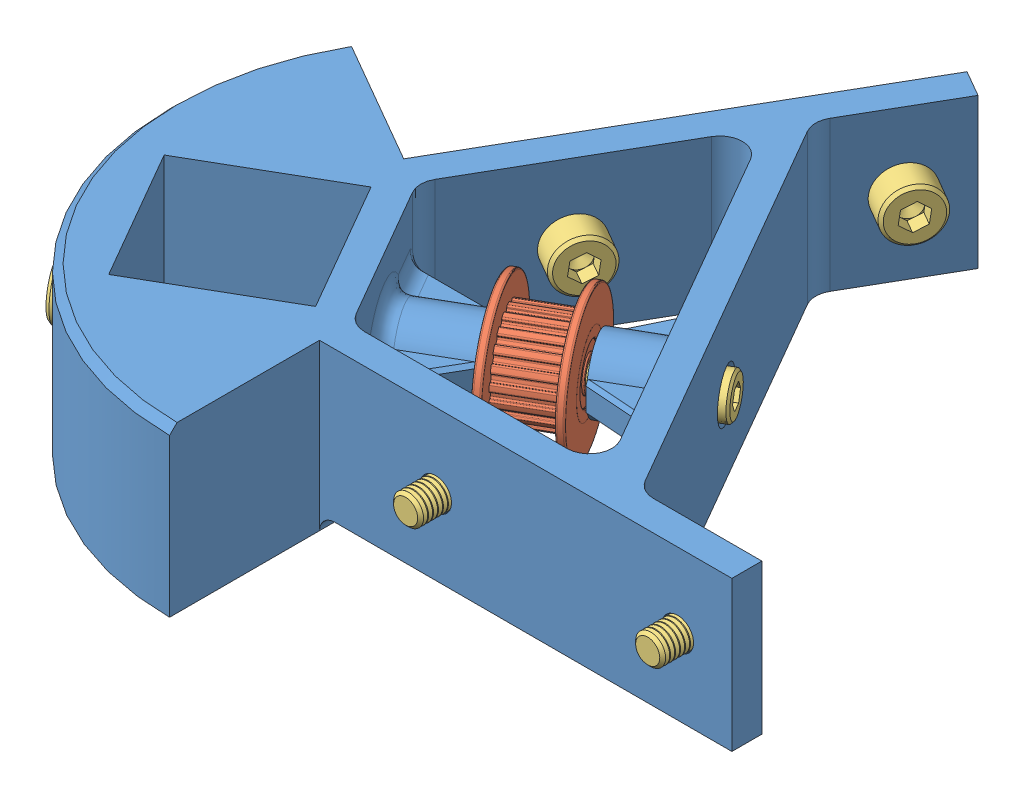
SolidWorks assembly Timing Assembly, configuration Default. Lengths in mm.
Overall size (92.71 23 94.2).
8 component instances, 3 part files, 14 mates.
Components (placement in the parent):
- Top Corner Support-1: Top Corner Support [Default] at origin size (92.71 23 94.2)
- Timing Pulley-1: Timing Pulley [Default] at (58.7441 9.7289 -33.9159) x (0.494167 0.152298 0.855923) z (-0.866025 0 0.5) size (17.85 17.85 9.2)
- socket head cap screw_am-1: socket head cap screw_am [B18.3.1M - 3 x 0.5 x 35 Hex SHCS -- 18SHX] at (72.0353 9.7289 -41.5896) x (-0.866025 0 0.5) z (-0.435421 -0.491563 -0.754171) size (38 5.5 5.5)
- socket head cap screw_am-2: socket head cap screw_am [B18.3.1M - 4 x 0.7 x 8 Hex SHCS -- 8SHX] at (95.7707 10 -18) x (0 0 1) z (-0.923728 -0.383049 0) size (12 7 7)
- socket head cap screw_am-3: socket head cap screw_am [B18.3.1M - 4 x 0.7 x 8 Hex SHCS -- 8SHX] at (63.4876 10 -18) x (0 0 1) z (-0.923728 -0.383049 0) size (12 7 7)
- socket head cap screw_am-4: socket head cap screw_am [B18.3.1M - 4 x 0.7 x 8 Hex SHCS -- 8SHX] at (47.3323 10 -45.9819) x (-0.866025 0 -0.5) z (-0.190925 0.924225 0.330691) size (12 7 7)
- socket head cap screw_am-5: socket head cap screw_am [B18.3.1M - 4 x 0.7 x 8 Hex SHCS -- 8SHX] at (63.4738 10 -73.9399) x (-0.866025 0 -0.5) z (-0.190925 0.924225 0.330691) size (12 7 7)
- socket head cap screw_am-6: socket head cap screw_am [B18.3.1M - 4 x 0.7 x 8 Hex SHCS -- 8SHX] at (14.3627 10 -8.2923) x (0.866025 0 -0.5) z (0.5 0 0.866025) size (12 7 7)
Mates (geometry in assembly coordinates):
- Concentric1: concentric: cylinder of Top Corner Support-1 through (35.7227 9.7289 -20.6245) axis (0.866025 0 -0.5) radius 1.25; cylinder of Timing Pulley-1 through (65.7339 9.7289 -37.9515) axis (-0.866025 0 0.5) radius 1.5
- Distance1: distance = 0.8473 mm: plane of Top Corner Support-1 through (50.909 10 -29.3923) normal (0.866025 0 -0.5); plane of Timing Pulley-1 through (51.6427 9.7289 -29.8159) normal (-0.866025 0 0.5)
- Concentric2: concentric: cylinder of Top Corner Support-1 through (69.4372 9.7289 -40.0896) axis (0.866025 0 -0.5) radius 2.75; cylinder of socket head cap screw_am-1 through (99.5316 9.7289 -57.4646) axis (0.866025 0 -0.5) radius 2.75
- Coincident2: coincident: plane of Top Corner Support-1 through (69.4372 9.7289 -40.0896) normal (0.866025 0 -0.5); plane of socket head cap screw_am-1 through (68.7613 12.1238 -41.2603) normal (-0.866025 0 0.5)
- Concentric3: concentric: cylinder of Top Corner Support-1 through (35.1989 10 -52.9871) axis (0.866025 0 0.5) radius 2.125; cylinder of socket head cap screw_am-4 through (74.8286 10 -30.1069) axis (0.866025 0 0.5) radius 3.5
- Concentric4: concentric: cylinder of Top Corner Support-1 through (51.3405 10 -80.9451) axis (0.866025 0 0.5) radius 2.125; cylinder of socket head cap screw_am-5 through (90.9701 10 -58.0649) axis (0.866025 0 0.5) radius 3.5
- Concentric5: concentric: cylinder of Top Corner Support-1 through (63.4876 10 -3.9896) axis (0 0 -1) radius 2.125; cylinder of socket head cap screw_am-3 through (63.4876 10 -49.75) axis (0 0 -1) radius 3.5
- Concentric6: concentric: cylinder of Top Corner Support-1 through (95.7707 10 -3.9896) axis (0 0 -1) radius 2.125; cylinder of socket head cap screw_am-2 through (95.7707 10 -49.75) axis (0 0 -1) radius 3.5
- Concentric7: concentric: cylinder of Top Corner Support-1 through (26.4961 10 -15.2975) axis (-0.866025 0 0.5) radius 2.125; cylinder of socket head cap screw_am-6 through (-13.1336 10 7.5827) axis (-0.866025 0 0.5) radius 3.5
- Coincident3: coincident: plane of Top Corner Support-1 through (17.8268 10 -10.2923) normal (-0.866025 0 0.5); plane of socket head cap screw_am-6 through (17.8268 13.5 -10.2923) normal (0.866025 0 -0.5)
- Coincident4: coincident: plane of Top Corner Support-1 through (49.9808 20 -14) normal (0 0 -1); plane of socket head cap screw_am-3 through (62.1469 13.233 -14) normal (0 0 1)
- Coincident5: coincident: plane of Top Corner Support-1 through (103 20 -14) normal (0 0 -1); plane of socket head cap screw_am-2 through (94.4301 13.233 -14) normal (0 0 1)
- Coincident6: coincident: plane of Top Corner Support-1 through (50.6216 20 -59.6791) normal (0.866025 0 0.5); plane of socket head cap screw_am-4 through (42.2508 8.6635 -45.1805) normal (-0.866025 0 -0.5)
- Coincident7: coincident: plane of Top Corner Support-1 through (56.3951 20 -69.6791) normal (0.866025 0 0.5); plane of socket head cap screw_am-5 through (58.3923 8.6635 -73.1385) normal (-0.866025 0 -0.5)
